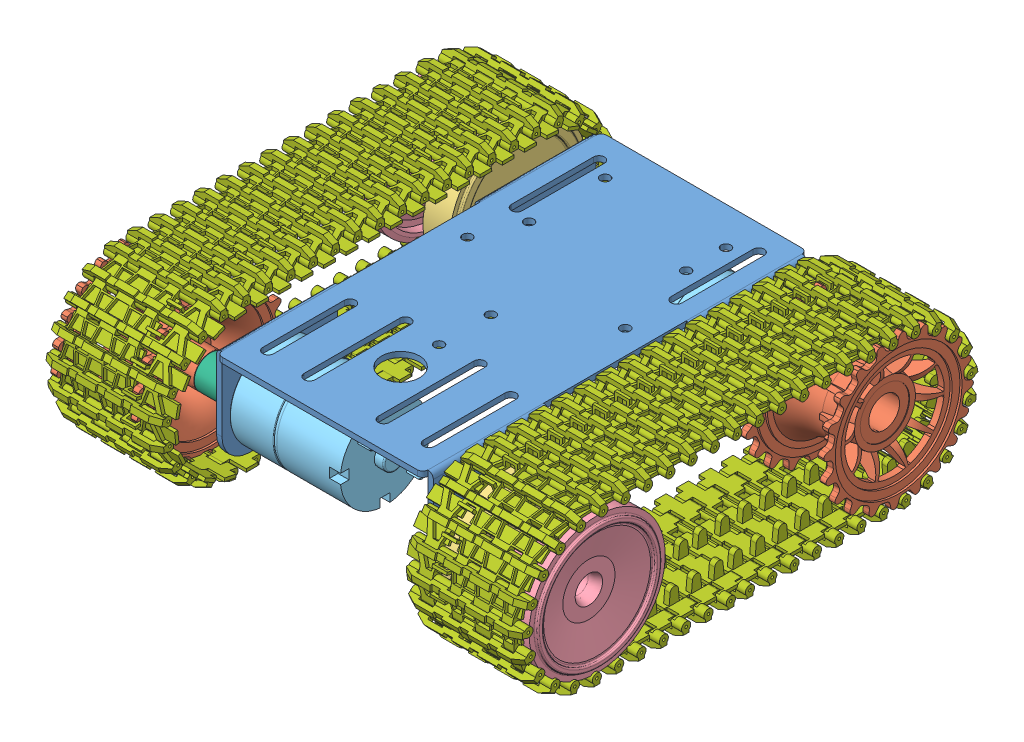
SolidWorks assembly Mini TP101 Smart Tank Chassis, configuration Default. Lengths in mm.
Overall size (173.8 71.3 180.56).
13 component instances, 7 part files, 30 mates.
Components (placement in the parent):
- Base Frame-1: Base Frame [Default] at (60.6644 78.7904 111.7014) size (79 37 140)
- DriverWheel-1: DriverWheel [Default] at (-9.5356 57.0404 166.6012) x (1 0 0) z (0 0.924225 0.381849) size (31.4 54.59 54.59)
- DriverWheel-2: DriverWheel [Default] at (130.8644 57.0404 56.8017) x (-1 0 0) z (0 -0.057411 -0.998351) size (31.4 54.59 54.59)
- FreeWheel_a-1: FreeWheel_a [Default] at (113.4144 57.1904 166.6014) x (0 0.96658 -0.256365) z (0 0.256365 0.96658) size (49.65 25.15 49.65)
- FreeWheel_b-1: FreeWheel_b [Default] at (120.0644 57.1904 166.6014) x (0 1 0) z (0 0 1) size (49.6 27.5 49.6)
- HTE-33GB-520-18.7 Motor-1: HTE-33GB-520-18.7 Motor [Default] at (82.1644 57.0103 62.8016) x (0 -0.999987 -0.005025) z (-1 0 0) size (32.75 32.75 56.05)
- Motor Horn-1: Motor Horn [Default] at (100.6644 57.0404 56.8017) x (1 0 0) z (0 0.057411 0.998351) size (23 11.9 11.9)
- FreeWheel_a-2: FreeWheel_a [Default] at (7.9144 57.1904 56.8014) x (0 -0.703844 0.710354) z (0 0.710354 0.703844) size (49.65 25.15 49.65)
- FreeWheel_b-2: FreeWheel_b [Default] at (1.2644 57.1904 56.8014) x (0 -0.876069 -0.482185) z (0 -0.482185 0.876069) size (49.6 27.5 49.6)
- HTE-33GB-520-18.7 Motor-2: HTE-33GB-520-18.7 Motor [Default] at (39.1644 57.0103 160.6013) x (0 -0.999987 0.005025) z (1 0 0) size (32.75 32.75 56.05)
- Motor Horn-2: Motor Horn [Default] at (20.6644 57.0404 166.6012) x (-1 0 0) z (0 -0.924225 -0.381849) size (23 11.9 11.9)
- SinglePart Crawler-1: SinglePart Crawler [Default] at (125.1144 31.4354 111.7366) x (1 0 0) z (0 0.001366 0.999999) size (44.5 59.42 169.22)
- SinglePart Crawler-2: SinglePart Crawler [Default] at (-3.7856 31.4354 111.6663) x (-1 0 0) z (0 0.001366 -0.999999) size (44.5 59.42 169.22)
Mates (geometry in assembly coordinates):
- Concentric1: concentric: circle of assembly; circle of assembly; circle of FreeWheel_a-1; circle of FreeWheel_b-1
- Coincident1: coincident: plane of assembly; plane of assembly; plane of FreeWheel_a-1 through (120.0644 57.1904 166.6014) normal (1 0 0); plane of FreeWheel_b-1 through (120.0644 57.1904 166.6014) normal (-1 0 0)
- Concentric2: concentric: circle of assembly; circle of assembly; circle of FreeWheel_a-2; circle of FreeWheel_b-2
- Coincident2: coincident: plane of assembly; plane of assembly; plane of FreeWheel_a-2 through (1.2644 57.1904 56.8014) normal (-1 0 0); plane of FreeWheel_b-2 through (1.2644 57.1904 56.8014) normal (1 0 0)
- Concentric3: concentric: cylinder of assembly; cylinder of assembly; cylinder of Base Frame-1 through (21.1644 57.0404 166.6014) axis (1 0 0) radius 5.25; cylinder of HTE-33GB-520-18.7 Motor-2 through (20.6644 57.0404 166.6012) axis (1 0 0) radius 4.875
- Concentric4: concentric: cylinder of assembly; cylinder of assembly; cylinder of Base Frame-1 through (21.1644 56.9404 146.7014) axis (1 0 0) radius 1.5; cylinder of HTE-33GB-520-18.7 Motor-2 through (23.1644 56.9404 146.7014) axis (-1 0 0) radius 1.25
- Coincident4: coincident: plane of assembly; plane of assembly; plane of Base Frame-1 through (23.1644 78.7904 181.7014) normal (1 0 0); plane of HTE-33GB-520-18.7 Motor-2 through (23.1644 57.0103 160.6013) normal (-1 0 0)
- Concentric5: concentric: cylinder of assembly; cylinder of assembly; cylinder of Base Frame-1 through (100.1644 57.0404 56.8014) axis (-1 0 0) radius 5.25; cylinder of HTE-33GB-520-18.7 Motor-1 through (100.6644 57.0404 56.8017) axis (-1 0 0) radius 4.875
- Concentric6: concentric: cylinder of assembly; cylinder of assembly; cylinder of Base Frame-1 through (100.1644 56.9404 76.7014) axis (-1 0 0) radius 1.5; cylinder of HTE-33GB-520-18.7 Motor-1 through (98.1644 56.9404 76.7014) axis (1 0 0) radius 1.25
- Coincident5: coincident: plane of assembly; plane of assembly; plane of Base Frame-1 through (98.1644 78.7904 181.7014) normal (-1 0 0); plane of HTE-33GB-520-18.7 Motor-1 through (98.1644 57.0103 62.8016) normal (1 0 0)
- Concentric7: concentric: cylinder of assembly; cylinder of assembly; cylinder of HTE-33GB-520-18.7 Motor-1 through (108.9644 57.0404 56.8017) axis (-1 0 0) radius 2.5; cylinder of Motor Horn-1 through (100.6644 57.0404 56.8017) axis (-1 0 0) radius 2.5
- Coincident6: coincident: plane of assembly; plane of assembly; plane of HTE-33GB-520-18.7 Motor-1 through (100.6644 57.0404 56.8017) normal (1 0 0); plane of Motor Horn-1 through (100.6644 56.6988 50.8615) normal (-1 0 0)
- Concentric8: concentric: cylinder of assembly; cylinder of assembly; cylinder of HTE-33GB-520-18.7 Motor-2 through (12.3644 57.0404 166.6012) axis (1 0 0) radius 2.5; cylinder of Motor Horn-2 through (20.6644 57.0404 166.6012) axis (1 0 0) radius 2.5
- Coincident7: coincident: plane of assembly; plane of assembly; plane of HTE-33GB-520-18.7 Motor-2 through (20.6644 57.0404 166.6012) normal (-1 0 0); plane of Motor Horn-2 through (20.6644 62.5395 168.8732) normal (1 0 0)
- Concentric9: concentric: cylinder of assembly; cylinder of assembly; cylinder of DriverWheel-2 through (130.8644 57.0404 56.8017) axis (1 0 0) radius 4.125; cylinder of Motor Horn-1 through (100.6644 57.0404 56.8017) axis (-1 0 0) radius 4
- Parallel1: parallel: plane of assembly; plane of assembly; plane of DriverWheel-2 through (130.4065 59.5045 53.4936) normal (0 -0.998351 0.057411); plane of Motor Horn-1 through (115.7644 59.5245 59.9368) normal (0 0.998351 -0.057411)
- Coincident9: coincident: plane of assembly; plane of assembly; plane of DriverWheel-2 through (115.6644 57.3849 62.7918) normal (-1 0 0); plane of Motor Horn-1 through (115.6644 56.8108 52.8083) normal (1 0 0)
- Concentric10: concentric: cylinder of assembly; cylinder of assembly; cylinder of DriverWheel-1 through (-9.5356 57.0404 166.6012) axis (-1 0 0) radius 4.125; cylinder of Motor Horn-2 through (20.6644 57.0404 166.6012) axis (1 0 0) radius 4
- Parallel2: parallel: plane of assembly; plane of assembly; plane of DriverWheel-1 through (-9.0778 60.974 165.3591) normal (0 -0.381849 0.924225); plane of Motor Horn-2 through (5.5644 54.894 163.2258) normal (0 0.381849 -0.924225)
- Coincident11: coincident: plane of assembly; plane of assembly; plane of DriverWheel-1 through (5.6644 51.4951 164.3101) normal (1 0 0); plane of Motor Horn-2 through (5.6644 60.7373 168.1286) normal (-1 0 0)
- Concentric11: concentric: cylinder of assembly; cylinder of assembly; cylinder of Base Frame-1 through (21.1644 57.1904 56.8014) axis (1 0 0) radius 3.75; cylinder of FreeWheel_a-2 through (18.4144 57.1904 56.8014) axis (-1 0 0) radius 2
- Concentric12: concentric: cylinder of assembly; cylinder of assembly; cylinder of Base Frame-1 through (100.1644 57.1904 166.6014) axis (-1 0 0) radius 3.75; cylinder of FreeWheel_a-1 through (102.9144 57.1904 166.6014) axis (1 0 0) radius 2
- Coincident13: coincident: plane of assembly; plane of assembly; plane of DriverWheel-1 through (-25.2356 57.0404 166.6012) normal (-1 0 0); plane of FreeWheel_b-2 through (-25.2356 57.1904 56.8014) normal (-1 0 0)
- Coincident14: coincident: plane of assembly; plane of assembly; plane of DriverWheel-2 through (146.5644 57.0404 56.8017) normal (1 0 0); plane of FreeWheel_b-1 through (146.5644 57.1904 166.6014) normal (1 0 0)
- Coincident17: coincident: plane of assembly; plane of assembly; plane of DriverWheel-2 through (144.3644 57.0404 56.8017) normal (-1 0 0); plane of SinglePart Crawler-1 through (144.3644 59.352 31.0569) normal (1 0 0)
- Concentric14: concentric: cylinder of assembly; cylinder of assembly; cylinder of Motor Horn-1 through (123.6644 57.0404 56.8017) axis (1 0 0) radius 1.25; cylinder of SinglePart Crawler-1 through (125.6144 57.0404 56.8015) axis (-1 0 0) radius 0.5
- Concentric15: concentric: cylinder of assembly; cylinder of assembly; cylinder of FreeWheel_a-1 through (102.9144 57.1904 166.6014) axis (1 0 0) radius 2; cylinder of SinglePart Crawler-1 through (125.6144 57.1904 166.6014) axis (-1 0 0) radius 0.5
- Coincident18: coincident: plane of assembly; plane of assembly; plane of DriverWheel-1 through (-23.0356 57.0404 166.6012) normal (1 0 0); plane of SinglePart Crawler-2 through (-23.0356 74.1373 185.9876) normal (-1 0 0)
- Concentric16: concentric: cylinder of assembly; cylinder of assembly; cylinder of DriverWheel-1 through (-9.5356 57.0404 166.6012) axis (-1 0 0) radius 1.75; cylinder of SinglePart Crawler-2 through (-4.2856 57.0404 166.6013) axis (1 0 0) radius 0.5
- Concentric17: concentric: cylinder of assembly; cylinder of assembly; cylinder of FreeWheel_a-2 through (18.4144 57.1904 56.8014) axis (-1 0 0) radius 2; cylinder of SinglePart Crawler-2 through (-4.2856 57.1904 56.8014) axis (1 0 0) radius 0.5
